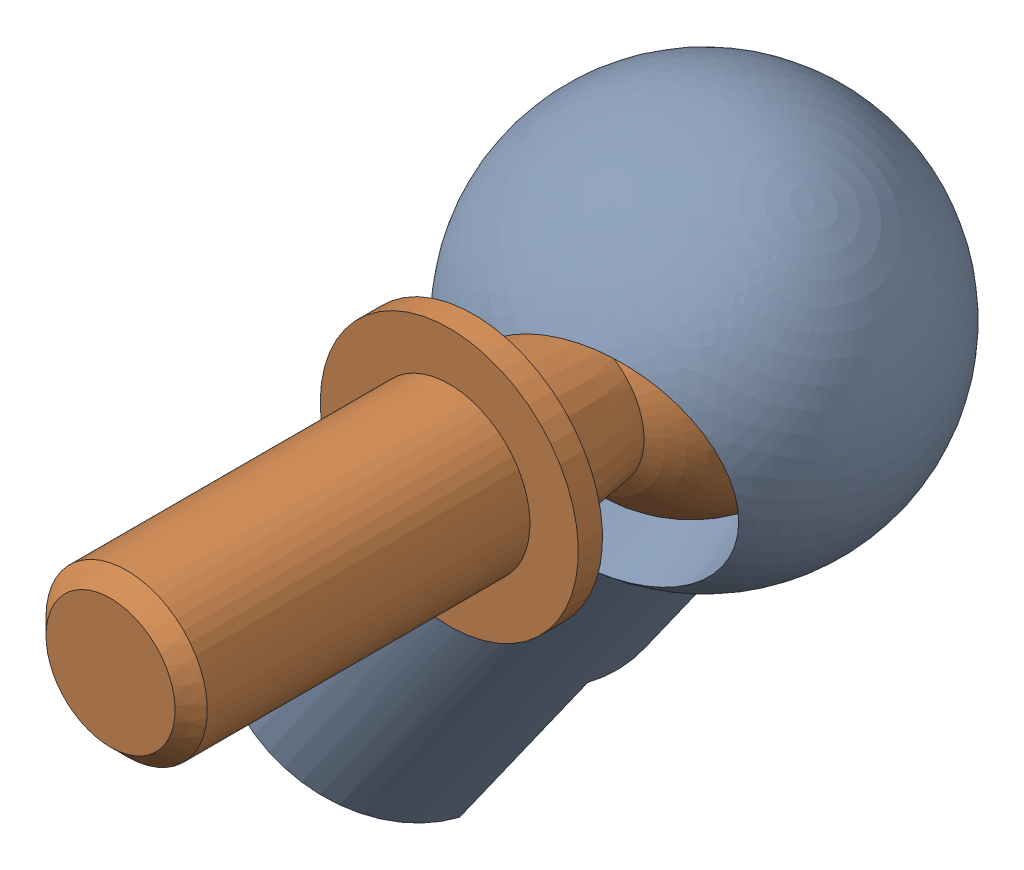
SolidWorks assembly ball joint, configuration Default. Lengths in mm.
Overall size (51.2 55.52 52.67).
2 component instances, 2 part files, 2 mates.
Components (placement in the parent):
- socket-1: socket [Default] at (-24.3903 10.1361 -4.0976) x (0.776536 -0.549238 -0.308756) z (0.244338 -0.189184 0.951057) size (24 47 21.56)
- ball-1: ball [Default] at (-3.78 38.4056 -2.5496) x (-0.966817 0.255471 0) z (0 0 1) size (16 16 44)
Mates (geometry in assembly coordinates):
- Concentric1: concentric: sphere of socket-1; sphere of ball-1
- LimitAngle4: limit planar angle = 0.314159 rad anti-aligned: line of ball-1 through (-3.78 38.4056 10.9504) axis (0 0 -1); line of socket-1 through (-2.9537 37.7658 0.6668) axis (0.244338 -0.189184 0.951057)
